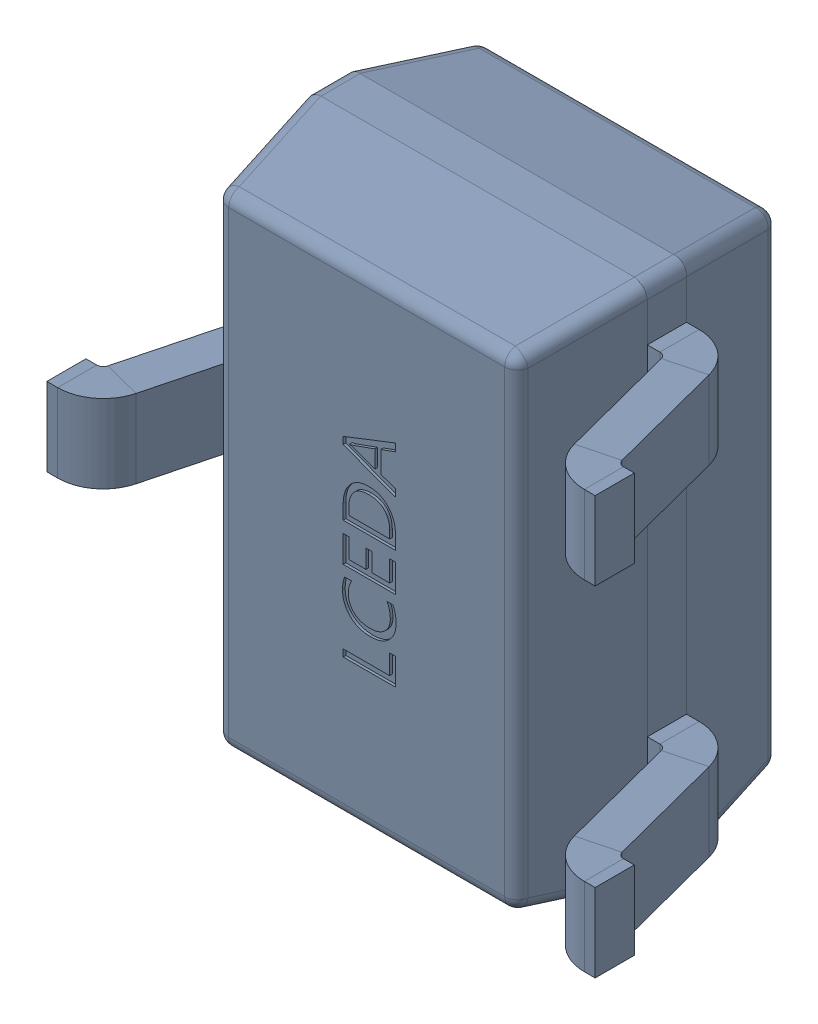
SolidWorks assembly D44, configuration Défaut. Lengths in mm.
Overall size (2.1 2 1.18).
4 component instances, 1 part files, 0 mates.
Components (placement in the parent):
- SOT-323-1: SOT-323 [Défaut] at (8.0797 -12.3051 -0.4818) x (1 0 0) z (0 0 -1) size (2.1 2 1.18)
  - D1.step-1: D1.step [Défaut] at (5.0775 -6.7805 1.6001) size (2.1 2 1.18)
    - SOT-323_L2.0-W1.3-P1.30-LS2.1-BR.step-1: SOT-323_L2.0-W1.3-P1.30-LS2.1-BR.step [Défaut] at origin size (2.1 2 1.18)
      - COMPOUND.step_247-1: COMPOUND.step_247 [Défaut] at origin size (2.1 2 1.18)
